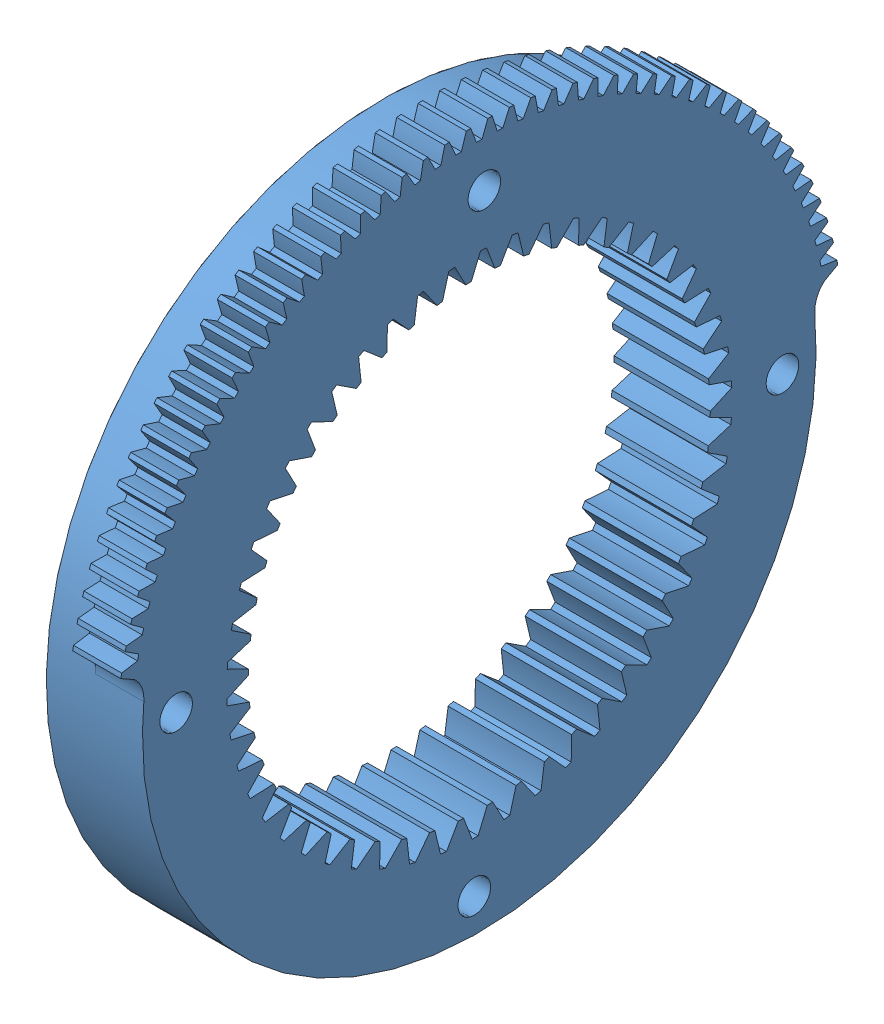
SolidWorks assembly UnionDeAnilloConEngraneExternoParaEncoer, configuration Predeterminado. Lengths in mm.
Overall size (10 72.79 74.49).
3 component instances, 3 part files, 1 mates.
Components (placement in the parent):
- AnilloConDobleEngraneParaEncoder-2: AnilloConDobleEngraneParaEncoder [ISO - Spur gear 0.7M 106T 20PA 5FW ---S106A75H50L65.0N] at origin size (5 75.58 75.6) (hidden)
- anilloParaEncoderP1-2: anilloParaEncoderP1 [ISO - Internal spur gear 1M 50T 20PA 10FW ---S50S70OD 1.0AF] at (-5 0 0) x (1 0 0) z (0 0.016591 0.999862) size (10 70 70) (hidden)
- AnilloCompatibleEncoder-1: AnilloCompatibleEncoder [Predeterminado] at origin size (10 72.79 74.49)
Mates (geometry in assembly coordinates):
- Concéntrica1: concentric: circle of ?; circle of anilloParaEncoderP1-2
